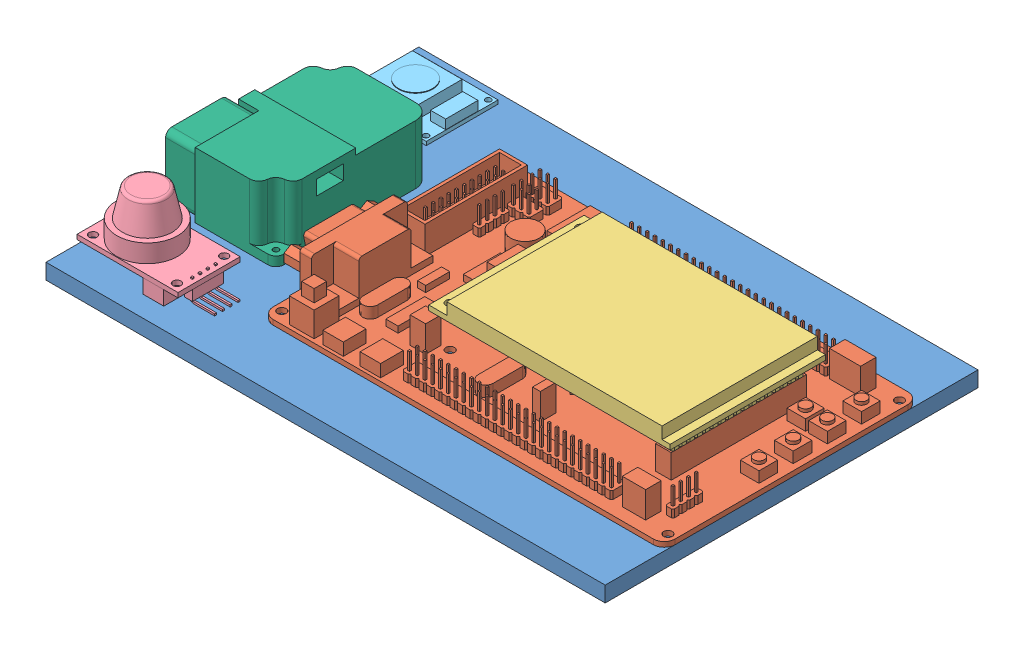
SolidWorks assembly MACM020000_CenterAssy, configuration 默认. Lengths in mm.
Overall size (180 27.66 120).
7 component instances, 6 part files, 12 mates.
Components (placement in the parent):
- MACM020001_CenterBoard-1: MACM020001_CenterBoard [默认] at (24.9089 -7.4993 180) size (180 5 120)
- MACM020100_STM32Assy-1: MACM020100_STM32Assy [默认] at (-88.6911 4.1308 179.3607) x (0 0 -1) z (1 0 0) size (82 19.9 134)
  - MACM020101_STM32-1: MACM020101_STM32 [默认] at (-0.6393 -6.6301 138.9) size (82 16.3 134)
  - MACM020102_LCD-1: MACM020102_LCD [默认] at (-0.6393 6.4699 150.65) size (50 15.8 77.7)
- MACM020211_COSensor-1: MACM020211_COSensor [默认] at (-43.8411 3.8007 225) x (0 0 -1) z (1 0 0) size (20 21.46 38.35)
- MACM020221_CH2OSensor-1: MACM020221_CH2OSensor [默认] at (-47.3411 -0.6993 136.55) x (0 0 -1) z (1 0 0) size (23.1 6.2 25.5)
- MACM020231_PMSensor-1: MACM020231_PMSensor [默认] at (-42.3411 0.5007 180) x (0 0 1) z (1 0 0) size (50 21 36)
Mates (geometry in assembly coordinates):
- 重合1: coincident aligned: plane of MACM020001_CenterBoard-1 through (114.9089 -2.4993 240) normal (1 0 0); plane of MACM020100_STM32Assy-1/MACM020101_STM32-1 through (114.9089 -0.8993 217.5) normal (1 0 0)
- 重合2: coincident anti-aligned: plane of MACM020001_CenterBoard-1 through (24.9089 -2.4993 180) normal (0 1 0); plane of MACM020100_STM32Assy-1/MACM020101_STM32-1 through (111.4089 -2.4993 217.5) normal (0 -1 0)
- 重合3: coincident anti-aligned: plane of MACM020001_CenterBoard-1 through (24.9089 -7.4993 180) normal (0 0 1); plane of MACM020100_STM32Assy-1/MACM020101_STM32-1 through (50.2089 -2.4993 180) normal (0 0 -1)
- 重合4: coincident anti-aligned: plane of MACM020001_CenterBoard-1 through (24.9089 -2.4993 180) normal (0 1 0); plane of MACM020231_PMSensor-1 through (-56.0911 -2.4993 157.5) normal (0 -1 0)
- 距离2: distance = 3 mm aligned: plane of MACM020001_CenterBoard-1 through (-65.0911 -2.4993 240) normal (-1 0 0); plane of MACM020231_PMSensor-1 through (-62.0911 0.0007 202.5) normal (-1 0 0)
- 距离1: distance = 35 mm aligned: plane of MACM020231_PMSensor-1 through (-28.5911 -2.4993 205) normal (0 0 1); plane of MACM020001_CenterBoard-1 through (-65.0911 -2.4993 240) normal (0 0 1)
- 距离3: distance = 5 mm aligned: plane of MACM020221_CH2OSensor-1 through (-34.5911 0.5007 125) normal (0 0 -1); plane of MACM020001_CenterBoard-1 through (-65.0911 -2.4993 120) normal (0 0 -1)
- 距离4: distance = 5 mm aligned: plane of MACM020001_CenterBoard-1 through (-65.0911 -2.4993 240) normal (-1 0 0); plane of MACM020221_CH2OSensor-1 through (-60.0911 0.5007 148.1) normal (-1 0 0)
- 距离5: distance = 1 mm anti-aligned: plane of MACM020001_CenterBoard-1 through (24.9089 -2.4993 180) normal (0 1 0); plane of MACM020221_CH2OSensor-1 through (-47.3411 -1.4993 136.55) normal (0 -1 0)
- 距离6: distance = 5 mm aligned: plane of MACM020211_COSensor-1 through (-60.0911 5.3007 235) normal (-1 0 0); plane of MACM020001_CenterBoard-1 through (-65.0911 -2.4993 240) normal (-1 0 0)
- 距离7: distance = 5 mm aligned: plane of MACM020211_COSensor-1 through (-27.5911 5.3007 235) normal (0 0 1); plane of MACM020001_CenterBoard-1 through (-65.0911 -2.4993 240) normal (0 0 1)
- 距离8: distance = 1.5 mm anti-aligned: plane of MACM020001_CenterBoard-1 through (24.9089 -2.4993 180) normal (0 1 0); plane of MACM020211_COSensor-1 through (-43.8411 -0.9993 225) normal (0 -1 0)
